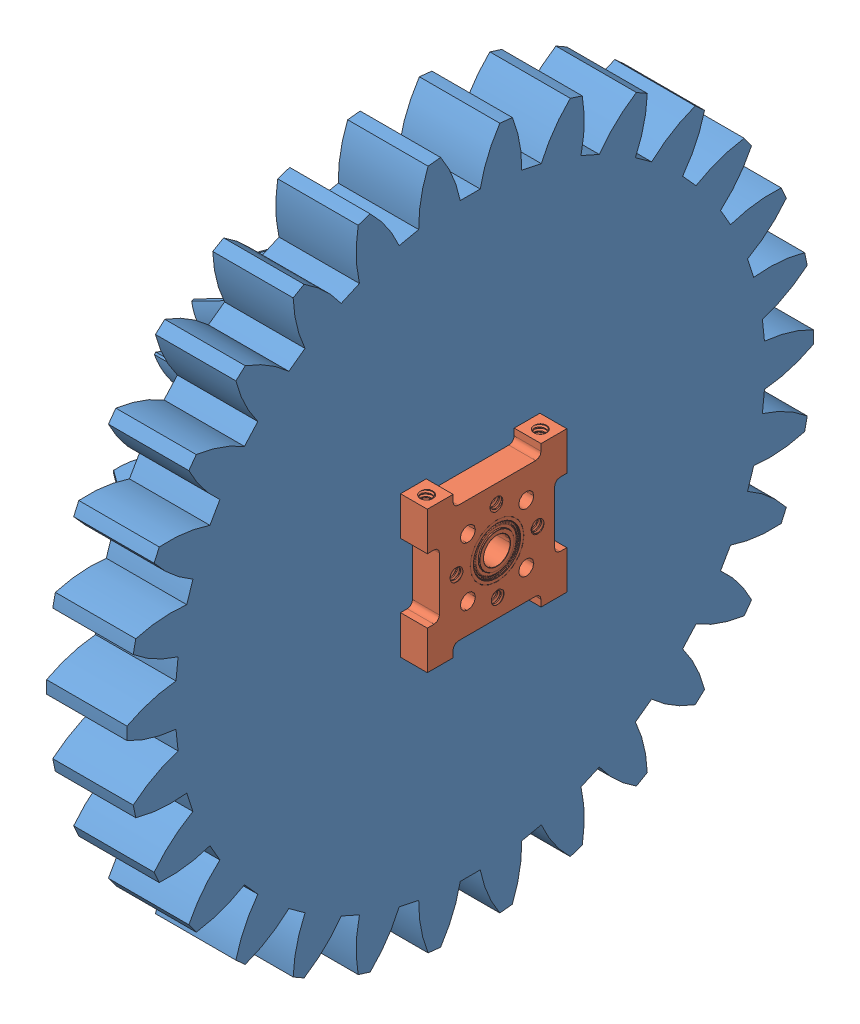
SolidWorks assembly ARMUS-101-300, configuration Default. Lengths in mm.
Overall size (57.21 161.95 162.56).
3 component instances, 2 part files, 7 mates.
Components (placement in the parent):
- ARMUS-REV2-301-1: ARMUS-REV2-301 [Default] at origin size (50.86 161.95 162.56)
- Bore Side Tapped Pillow Block 1.25-1: Bore Side Tapped Pillow Block 1.25 [Default] at (-39.4159 7.6184 -28.3917) x (0 -1 0) z (0 0 1) size (33.54 6.35 33.02)
- Bore Side Tapped Pillow Block 1.25-2: Bore Side Tapped Pillow Block 1.25 [Default] at (4.8346 7.6184 -28.3917) x (0 -1 0) z (0 0 1) size (33.54 6.35 33.02)
Mates (geometry in assembly coordinates):
- Coincident1: coordinate: point of ARMUS-REV2-100-1
- Concentric1: concentric anti-aligned: cylinder of ARMUS-REV2-100-1 through (-86.1279 0 0) axis (1 0 0) radius 6.35; cylinder of Bore Side Tapped Pillow Block 1.25-1 through (-18.8631 0 0) axis (-1 0 0) radius 3.175
- Parallel1: parallel aligned: plane of ARMUS-REV2-100-1 through (0 0 0) normal (0 1 0); plane of Bore Side Tapped Pillow Block 1.25-1 through (-18.8504 13.9065 -10.414) normal (0 1 0)
- Coincident3: coincident anti-aligned: plane of ARMUS-REV2-100-1 through (-18.8504 0 0) normal (-1 0 0); plane of Bore Side Tapped Pillow Block 1.25-1 through (-18.8504 0 0) normal (1 0 0)
- Concentric2: concentric anti-aligned: cylinder of ARMUS-REV2-100-1 through (-86.1279 0 0) axis (1 0 0) radius 6.35; cylinder of Bore Side Tapped Pillow Block 1.25-2 through (25.3873 0 0) axis (-1 0 0) radius 3.175
- Parallel2: parallel aligned: plane of Bore Side Tapped Pillow Block 1.25-1 through (-18.8504 13.9065 -10.414) normal (0 1 0); plane of Bore Side Tapped Pillow Block 1.25-2 through (25.4 13.9065 -10.414) normal (0 1 0)
- Coincident4: coincident anti-aligned: plane of ARMUS-REV2-100-1 through (19.05 0 0) normal (1 0 0); plane of Bore Side Tapped Pillow Block 1.25-2 through (19.05 0 0) normal (-1 0 0)
